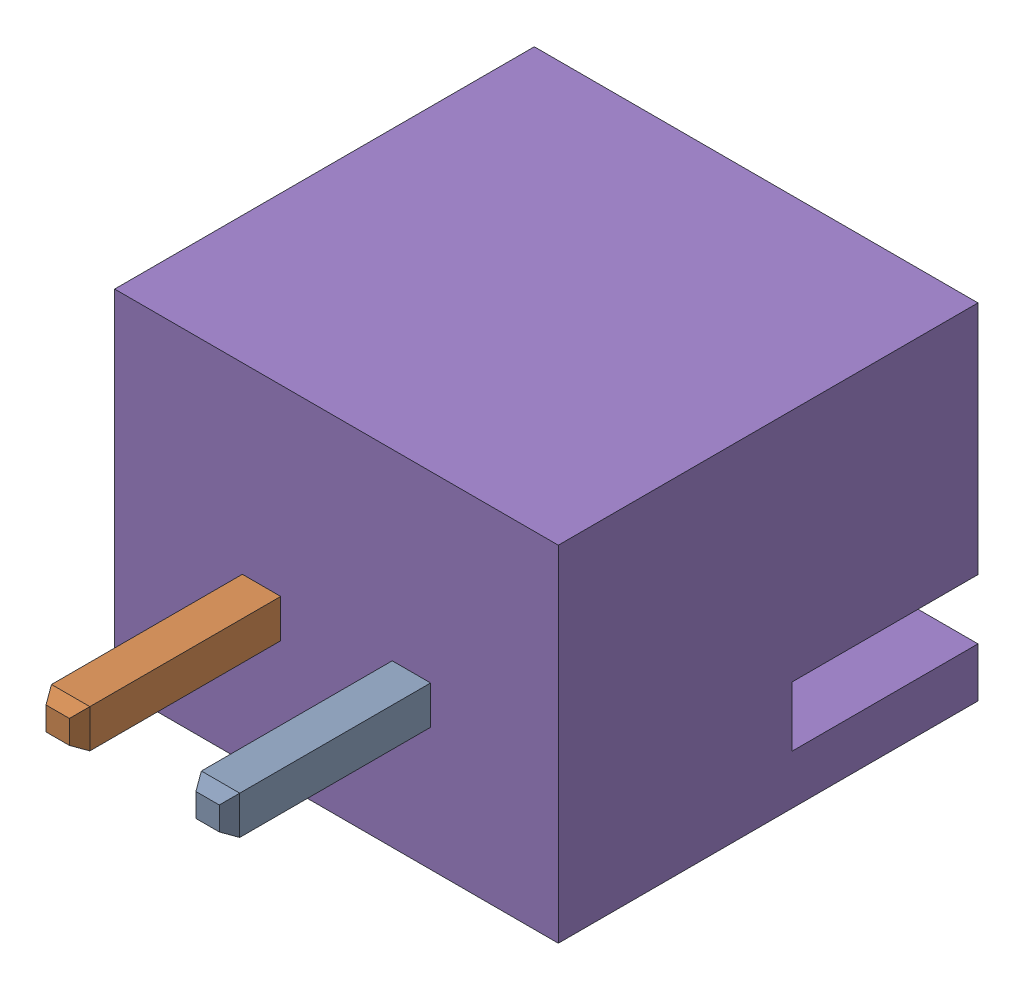
SolidWorks assembly P1-2, configuration Default. Lengths in mm.
Overall size (7.4 5.75 10.4).
6 component instances, 5 part files, 0 mates.
Components (placement in the parent):
- P1-subassembly-1-2-1: P1-subassembly-1-2 [Default] at (131.5051 81.6569 -0.3912) x (-1 0 0) z (0 -1 0) size (7.4 10.4 5.75)
  - User Library-JST B2B-XH-A-10-1: User Library-JST B2B-XH-A-10 [Default] at origin size (0.64 3.4 0.64)
  - User Library-JST B2B-XH-A-11-1: User Library-JST B2B-XH-A-11 [Default] at origin size (0.64 3.4 0.64)
  - User Library-JST B2B-XH-A-12-1: User Library-JST B2B-XH-A-12 [Default] at origin size (0.64 4.5 0.64)
  - User Library-JST B2B-XH-A-13-1: User Library-JST B2B-XH-A-13 [Default] at origin size (0.64 4.5 0.64)
  - User Library-JST B2B-XH-A-14-1: User Library-JST B2B-XH-A-14 [Default] at origin size (7.4 7 5.75)
